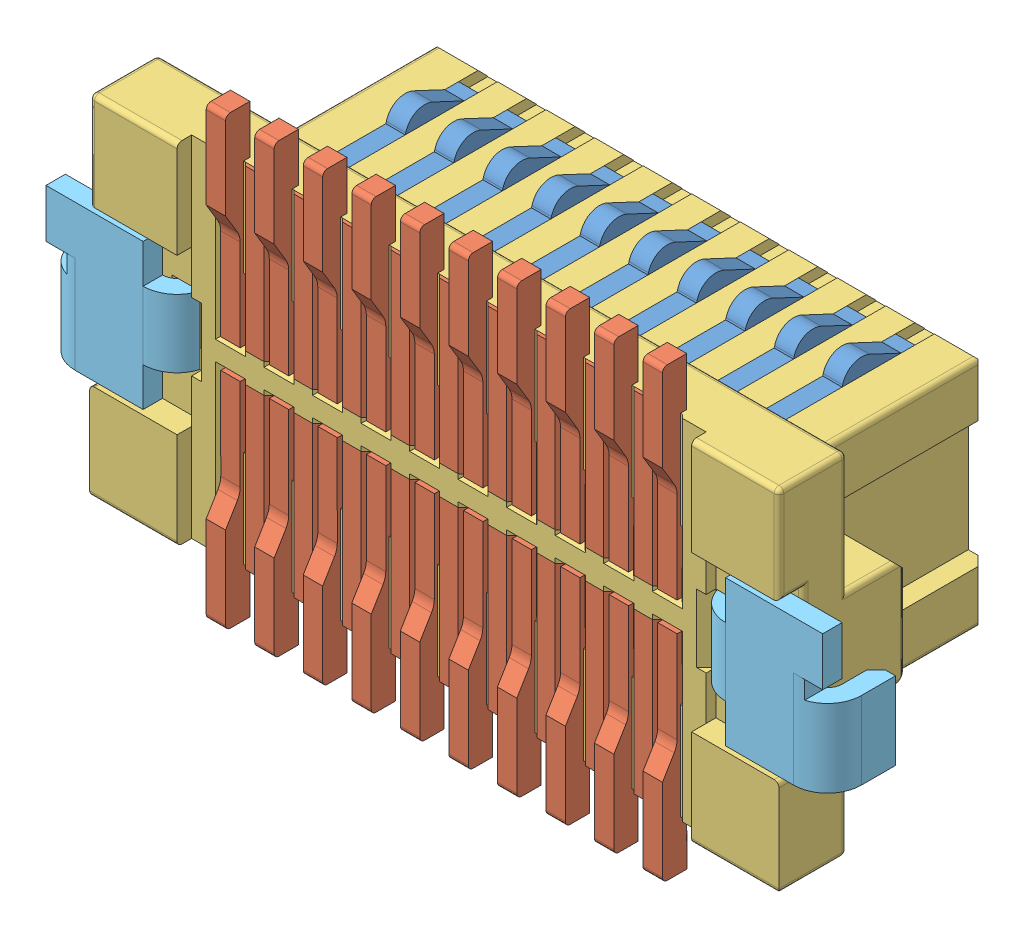
SolidWorks assembly J1.step, configuration 默认. Lengths in mm.
Overall size (8.1 4.6 2.91).
6 component instances, 5 part files, 0 mates.
Components (placement in the parent):
- Conn_Hirose_DF12B-20DS-0_5V_86_eec.step-1: Conn_Hirose_DF12B-20DS-0_5V_86_eec.step [默认] at (173.129 28.343 -0.4115) x (1 0 0) z (0 0 -1) size (8.1 4.6 2.91)
  - 1.step-1: 1.step [默认] at origin size (4.71 3.19 2.2)
  - 2.step-1: 2.step [默认] at origin size (4.78 4.6 0.25)
  - 3.step-1: 3.step [默认] at origin size (7.1 3.6 2.9)
  - Hirose_Electric.step-1: Hirose_Electric.step [默认] at (-0.0359 -0.0489 2.8995) size (1.46 0.76 0.02)
  - 4.step-1: 4.step [默认] at (-4.85 -1.5 0) size (8.1 1.5 0.7)
